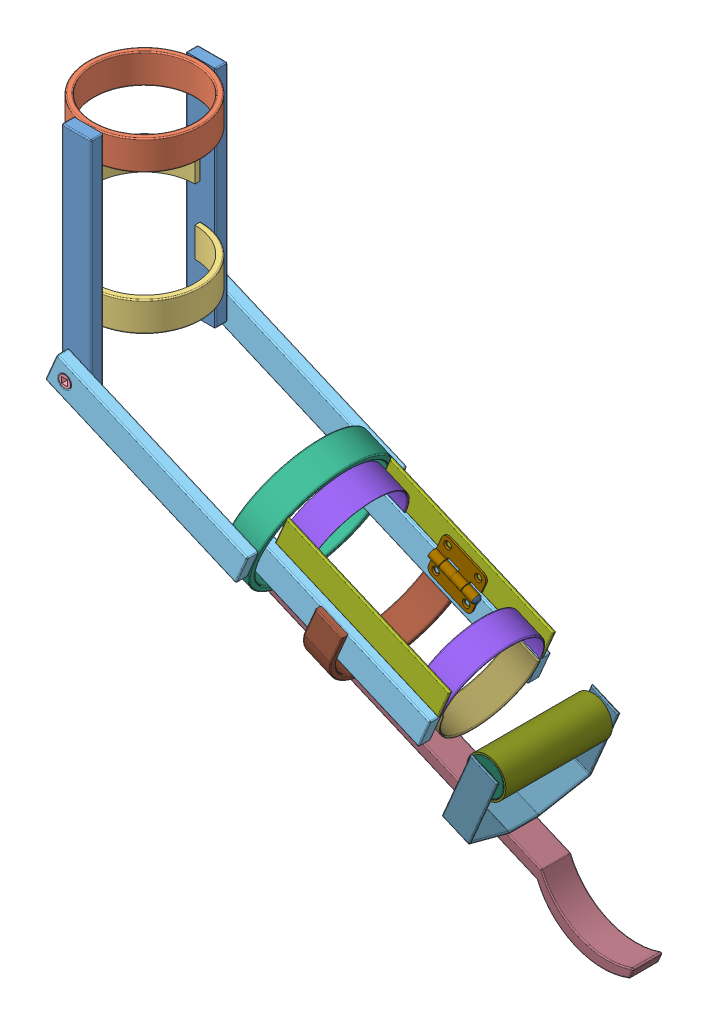
SolidWorks assembly Complete assembly-fin, configuration Default. Lengths in mm.
Overall size (474.41 446.9 156.78).
29 component instances, 16 part files, 40 mates.
Components (placement in the parent):
- bicep assembly-1: bicep assembly [Default] at (-92.7045 19.8561 -17.071) size (97.42 190 115)
  - Bicep bar-1: Bicep bar [Default] at (128.1601 130.47 134.6387) size (25 190 10)
  - Top ring-1: Top ring [Default] at (85.1987 167.1931 192.1387) x (0.999666 0 0.025831) z (-0.025831 0 0.999666) size (95 25 95)
  - Bicep bar-2: Bicep bar [Default] at (128.1601 130.47 239.6387) size (25 190 10)
  - Top ring half-1: Top ring half [Default] at (85.1987 104.1931 192.1387) size (47.5 25 95)
  - Top ring half-2: Top ring half [Default] at (85.1987 49.1931 192.1387) x (-1 0 0) z (0 0 -1) size (47.5 25 95)
- Pin-1: Pin [Default] at (-7.5058 34.5492 222.5677) size (10 10 20)
- Pin-2: Pin [Default] at (-7.5058 34.5492 107.5677) size (10 10 20)
- Forearm bar-1: Forearm bar [Default] at (45.7839 11.4953 232.5677) x (0.919557 -0.392956 0) z (0 0 1) size (175 25 10)
- Forearm bar-2: Forearm bar [Default] at (45.7839 11.4953 107.5677) x (0.919557 -0.392956 0) z (0 0 1) size (175 25 10)
- Foream ring-1: Foream ring [Default] at (142.5551 -27.8252 175.0677) x (0.341725 0.79967 -0.493712) z (-0.919557 0.392956 0) size (115 115 25)
- Forearm bar-5: Forearm bar [Default] at (183.7175 -47.4481 216.1904) x (0.919557 -0.392956 0) z (0 0 1) size (175 25 10)
- Forearm bar-6: Forearm bar [Default] at (183.7175 -47.4481 124.1424) x (0.919557 -0.392956 0) z (0 0 1) size (175 25 10)
- fortop assembly-1: fortop assembly [Default] at (92.0205 -75.7393 70.4041) x (0.919557 -0.392956 0) z (0 0 1) size (150.18 76.39 113.86)
  - fortop bar-1: fortop bar [Default] at (101.9454 93.1638 61.2383) size (150 25 2.5)
  - end ring-1: end ring [Default] at (178.7885 77.6629 106.2383) x (0 0 1) z (0 -1 0) size (85 25 42.5)
  - fortop bar-2: fortop bar [Default] at (101.9454 93.1638 148.7383) size (150 25 2.5)
  - end ring-2: end ring [Default] at (53.7885 77.6629 106.2383) x (0 0 1) z (0 -1 0) size (85 25 42.5)
  - Asm-1: Asm [По умолчанию] at (109.7346 105.6478 67.5563) x (-0.320793 -0.742457 -0.58809) z (0.302704 0.507974 -0.806432) size (45.28 52.94 37.22)
    - Part 1-1: Part 1 [По умолчанию] at (19.4176 18.3169 -10.8294) x (0.742457 -0.436715 -0.507974) z (0.320793 0.897475 -0.302704) size (22.6 7.2 40)
    - Part 1-2: Part 1 [По умолчанию] at (34.7993 -34.1773 -18.0242) x (-0.742457 0.436715 0.507974) z (-0.320793 -0.897475 0.302704) size (22.6 7.2 40)
    - Part 2-1: Part 2 [По умолчанию] at (18.5755 -26.1022 -11.2759) x (0.568066 -0.438042 -0.696721) z (0.320793 0.897475 -0.302704) size (7.2 7.2 42.52)
- forearm lower half ring-5: forearm lower half ring [Default] at (210.9018 -58.7479 181.8163) x (0 0 1) z (-0.392956 -0.919557 0) size (112.05 25 69.63)
- end ring half-1: end ring half [Default] at (285.8227 -77.2059 175.1674) x (0 0 -1) z (0.392956 0.919557 0) size (82.05 25.18 41.02)
- Hook bar-1: Hook bar [Default] at (190.9745 -127.6857 162.5677) x (0.919557 -0.392956 0) z (0 0 1) size (349.85 27.57 25)
- Handle assembly edit-1: Handle assembly edit [Default] at (204.3741 -169.0401 224.4379) x (0 0 -1) z (0.919557 -0.392956 0) size (104 85.88 41.31)
  - handle cover edit-1: handle cover edit [Default] at (63.6919 103.283 72.0112) size (104 77.72 25)
  - Handle-1: Handle [Default] at (4.3702 112.0432 84.5112) x (0 -0.849582 -0.527457) z (1 0 0) size (30 30 100)
- handle grip-1: handle grip [Default] at (326.1151 -99.2192 130.0677) x (0.68978 -0.724019 0) z (0 0 1) size (33 33 90)
Mates (geometry in assembly coordinates):
- Concentric1: concentric: cylinder of bicep assembly-1/Bicep bar-2 through (-7.5058 34.5492 207.5677) axis (0 0 1) radius 5; cylinder of Pin-1 through (-7.5058 34.5492 242.5677) axis (0 0 -1) radius 5
- Coincident1: coincident: plane of bicep assembly-1/Bicep bar-2 through (35.4556 150.3261 222.5677) normal (0 0 -1); plane of Pin-1 through (-7.5058 34.5492 222.5677) normal (0 0 -1)
- Concentric2: concentric: cylinder of bicep assembly-1/Bicep bar-1 through (-7.5058 34.5492 102.5677) axis (0 0 1) radius 5; cylinder of Pin-2 through (-7.5058 34.5492 127.5677) axis (0 0 -1) radius 5
- Concentric5: concentric: cylinder of Pin-1 through (-7.5058 34.5492 242.5677) axis (0 0 -1) radius 5; cylinder of Forearm bar-1 through (-7.5058 34.5492 232.5677) axis (0 0 1) radius 5
- Coincident5: coincident: plane of bicep assembly-1/Bicep bar-2 through (35.4556 150.3261 232.5677) normal (0 0 1); plane of Forearm bar-1 through (45.7839 11.4953 232.5677) normal (0 0 -1)
- Concentric6: concentric: cylinder of Pin-2 through (-7.5058 34.5492 127.5677) axis (0 0 -1) radius 5; cylinder of Forearm bar-2 through (-7.5058 34.5492 107.5677) axis (0 0 1) radius 5
- Coincident6: coincident: plane of bicep assembly-1/Bicep bar-1 through (35.4556 150.3261 117.5677) normal (0 0 -1); plane of Forearm bar-2 through (45.7839 11.4953 117.5677) normal (0 0 1)
- Parallel2: parallel: plane of Forearm bar-1 through (45.7839 11.4953 232.5677) normal (0 0 -1); plane of Forearm bar-2 through (45.7839 11.4953 117.5677) normal (0 0 1)
- Tangent5: tangent: plane of Forearm bar-1 through (45.7839 11.4953 232.5677) normal (0 0 -1); cylinder of Foream ring-1 through (119.5662 -18.0013 175.0677) axis (0.919557 -0.392956 0) radius 57.5
- Lock1: lock: unknown of Forearm bar-2; unknown of Foream ring-1
- Lock2: lock: unknown of Forearm bar-1; unknown of Foream ring-1
- Parallel9: parallel: plane of Forearm bar-1 through (45.7839 11.4953 232.5677) normal (0 0 -1); plane of Forearm bar-5 through (183.7175 -47.4481 226.1904) normal (0 0 1)
- Coincident20: coincident: plane of Foream ring-1 through (119.5662 -18.0013 175.0677) normal (-0.919557 0.392956 0); plane of Forearm bar-5 through (123.8452 -7.9878 226.1904) normal (-0.919557 0.392956 0)
- Coincident21: coincident: plane of Forearm bar-1 through (-14.0883 50.9556 242.5677) normal (0.392956 0.919557 0); plane of Forearm bar-5 through (123.8452 -7.9878 226.1904) normal (0.392956 0.919557 0)
- Lock3: lock: unknown of Foream ring-1; unknown of Forearm bar-5
- Parallel10: parallel: plane of Forearm bar-5 through (183.7175 -47.4481 216.1904) normal (0 0 -1); plane of Forearm bar-6 through (183.7175 -47.4481 134.1424) normal (0 0 1)
- Coincident23: coincident: plane of Forearm bar-5 through (284.7678 -76.7551 602.7496) normal (0.919557 -0.392956 0); plane of Forearm bar-6 through (284.7678 -76.7551 510.7016) normal (0.919557 -0.392956 0)
- Coincident24: coincident: plane of Forearm bar-5 through (123.8452 -7.9878 226.1904) normal (0.392956 0.919557 0); plane of Forearm bar-6 through (123.8452 -7.9878 134.1424) normal (0.392956 0.919557 0)
- Lock4: lock: unknown of Foream ring-1; unknown of Forearm bar-6
- Coincident25: coincident: plane of Forearm bar-6 through (183.7175 -47.4481 134.1424) normal (0 0 1); plane of fortop assembly-1/Asm-1/Part 1-2 through (225.1173 -66.5739 134.1424) normal (0 0 -1)
- Parallel12: parallel: plane of Forearm bar-5 through (123.8452 -7.9878 226.1904) normal (-0.919557 0.392956 0); plane of fortop assembly-1/fortop bar-2 through (158.8352 7.3525 221.6424) normal (-0.919557 0.392956 0)
- Parallel13: parallel: plane of Forearm bar-6 through (284.7678 -76.7551 510.7016) normal (0.919557 -0.392956 0); plane of fortop assembly-1/fortop bar-1 through (296.7688 -51.591 134.1424) normal (0.919557 -0.392956 0)
- Lock5: lock: unknown of Forearm bar-6; unknown of ?
- Coincident45: coincident: plane of Forearm bar-6 through (183.7175 -47.4481 124.1424) normal (0 0 -1); plane of forearm lower half ring-5 through (192.812 -37.4595 124.1424) normal (0 0 1)
- Parallel22: parallel: plane of Forearm bar-5 through (183.7175 -47.4481 226.1904) normal (0 0 1); plane of forearm lower half ring-5 through (192.812 -37.4595 226.1924) normal (0 0 -1)
- Coincident47: coincident: plane of Forearm bar-6 through (123.8452 -7.9878 134.1424) normal (0.392956 0.919557 0); plane of forearm lower half ring-5 through (192.812 -37.4595 119.1424) normal (0.392956 0.919557 0)
- Width1: width: plane of forearm lower half ring-5 through (187.9863 -48.7521 175.1674) normal (-0.919557 0.392956 0); plane of forearm lower half ring-5 through (210.9753 -58.576 175.1674) normal (0.919557 -0.392956 0); plane of Forearm bar-6 through (284.7678 -76.7551 510.7016) normal (0.919557 -0.392956 0); plane of Forearm bar-6 through (123.8452 -7.9878 134.1424) normal (-0.919557 0.392956 0)
- Parallel25: parallel: plane of Forearm bar-5 through (284.7678 -76.7551 602.7496) normal (0.919557 -0.392956 0); plane of end ring half-1 through (285.8227 -77.2059 175.1674) normal (0.919557 -0.392956 0)
- Coincident51: coincident: plane of Forearm bar-5 through (123.8452 -7.9878 226.1904) normal (0.392956 0.919557 0); plane of end ring half-1 through (262.8338 -67.382 216.1924) normal (0.392956 0.919557 0)
- Tangent9: tangent: plane of Forearm bar-6 through (183.7175 -47.4481 134.1424) normal (0 0 1); cylinder of end ring half-1 through (262.8338 -67.382 175.1674) axis (0.919557 -0.392956 0) radius 41.025
- Coincident53: coincident: plane of fortop assembly-1/end ring-1 through (286.9449 -74.5799 176.6424) normal (0.919557 -0.392956 0); plane of end ring half-1 through (285.8227 -77.2059 175.1674) normal (0.919557 -0.392956 0)
- Coincident54: coincident: plane of Foream ring-1 through (119.5662 -18.0013 175.0677) normal (-0.919557 0.392956 0); plane of Hook bar-1 through (96.4823 -72.0199 187.5677) normal (-0.919557 0.392956 0)
- Tangent10: tangent: cylinder of forearm lower half ring-5 through (188.0356 -48.6367 175.1674) axis (0.919557 -0.392956 0) radius 57.4786; plane of Hook bar-1 through (96.4823 -72.0199 187.5677) normal (0.392956 0.919557 0)
- Width2: width: plane of Hook bar-1 through (391.9206 -163.0071 187.5677) normal (0 0 1); plane of Hook bar-1 through (391.9206 -163.0071 162.5677) normal (0 0 -1); plane of Forearm bar-2 through (45.7839 11.4953 107.5677) normal (0 0 -1); plane of Forearm bar-1 through (45.7839 11.4953 242.5677) normal (0 0 1)
- Coincident56: coincident: plane of Hook bar-1 through (96.4823 -72.0199 187.5677) normal (0.392956 0.919557 0); plane of Handle assembly edit-1/handle cover edit-1 through (311.9793 -164.1087 187.9713) normal (-0.392956 -0.919557 0)
- Parallel27: parallel: plane of Forearm bar-5 through (284.7678 -76.7551 602.7496) normal (0.919557 -0.392956 0); plane of Handle assembly edit-1/handle cover edit-1 through (311.1783 -102.3627 160.746) normal (-0.919557 0.392956 0)
- Width3: width: plane of Handle assembly edit-1/handle cover edit-1 through (342.5215 -92.6367 123.0677) normal (0 0 -1); plane of Handle assembly edit-1/handle cover edit-1 through (333.5705 -113.583 227.0677) normal (0 0 1); plane of Hook bar-1 through (391.9206 -163.0071 187.5677) normal (0 0 1); plane of Hook bar-1 through (391.9206 -163.0071 162.5677) normal (0 0 -1)
- Lock6: lock: unknown of Hook bar-1; unknown of ?
- Concentric7: concentric: cylinder of Handle assembly edit-1/Handle-1 through (326.1151 -99.2192 130.0677) axis (0 0 1) radius 15; cylinder of handle grip-1 through (326.1151 -99.2192 220.0677) axis (0 0 -1) radius 15
- Coincident57: coincident: plane of Handle assembly edit-1/Handle-1 through (326.1151 -99.2192 220.0677) normal (0 0 1); plane of handle grip-1 through (326.1151 -99.2192 220.0677) normal (0 0 1)
